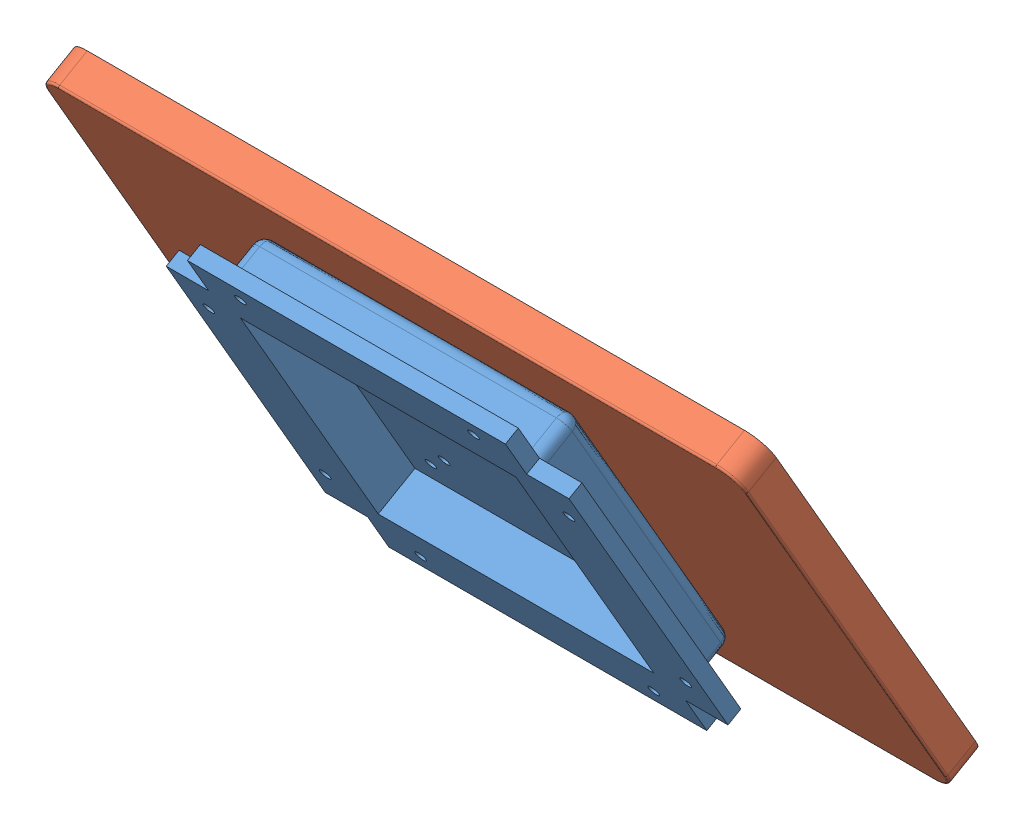
SolidWorks assembly displayholder, configuration Default. Lengths in mm.
Overall size (330 193.84 136.74).
3 component instances, 3 part files, 6 mates.
Components (placement in the parent):
- display_holder-1: display_holder [Default] at (-45.9887 145.697 189.1026) size (200 164.54 119.5) (hidden)
- bracket_display-1: bracket_display [Default] at (54.0113 137.7141 93.7199) x (-1 0 0) z (0 0.5 -0.866025) size (190 190 27)
- 13.3 inch Display-1: 13.3 inch Display [Default] at (54.0113 137.7141 93.7199) x (0 -0.866025 -0.5) z (0 0.5 -0.866025) size (208 330 16)
Mates (geometry in assembly coordinates):
- Coincident1: coincident anti-aligned: plane of display_holder-1 through (154.0113 206.4865 164.6026) normal (0 0.5 -0.866025); plane of bracket_display-1 through (54.0113 124.2141 117.1026) normal (0 -0.5 0.866025)
- Coincident2: coincident aligned: circle of display_holder-1; cylinder of bracket_display-1 through (139.0113 165.3455 155.861) axis (0 0.5 -0.866025) radius 2.5
- Coincident3: coincident aligned: cylinder of display_holder-1 through (109.0113 195.3263 163.9328) axis (0 0.5 -0.866025) radius 2.5; circle of bracket_display-1
- Coincident4: coincident anti-aligned: plane of bracket_display-1 through (54.0113 137.7141 93.7199) normal (0 0.5 -0.866025); plane of 13.3 inch Display-1 through (209.0113 56.3077 46.7199) normal (0 -0.5 0.866025)
- Concentric6: concentric anti-aligned: cylinder of bracket_display-1 through (4.0113 171.0154 136.0405) axis (0 0.5 -0.866025) radius 2.5; cylinder of 13.3 inch Display-1 through (4.0113 186.0154 110.0597) axis (0 -0.5 0.866025) radius 2.5
- Concentric7: concentric anti-aligned: cylinder of bracket_display-1 through (104.0113 171.0154 136.0405) axis (0 0.5 -0.866025) radius 2.5; cylinder of 13.3 inch Display-1 through (104.0113 186.0154 110.0597) axis (0 -0.5 0.866025) radius 2.5
